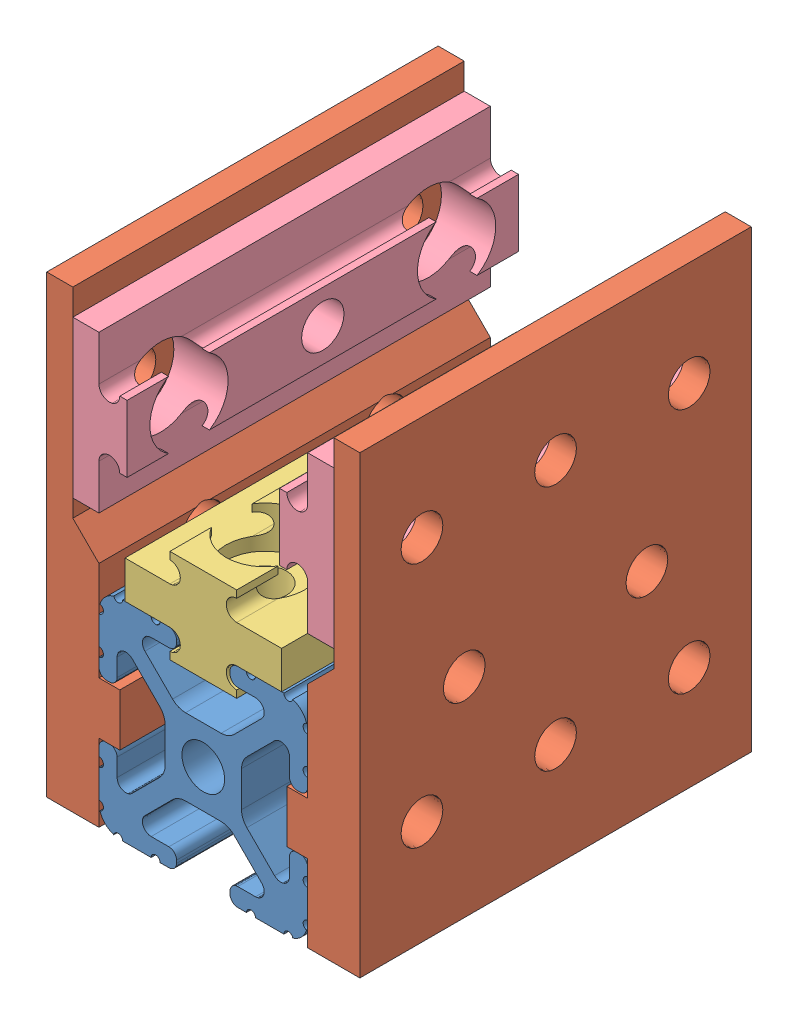
SolidWorks assembly LinearBearing_8020_pn6730, configuration Default. Lengths in mm.
Overall size (38.1 55.35 47.62).
6 component instances, 4 part files, 15 mates.
Components (placement in the parent):
- T-Slotted Framing_1.875-1: T-Slotted Framing_1.875 [47065T411] at origin size (25.4 25.4 47.62)
- BearingSide-1: BearingSide [Default] at (-19.05 -12.7 -23.8125) size (8.89 55.35 47.62)
- BearingSide-2: BearingSide [Default] at (19.05 -12.7 23.8125) x (-1 0 0) z (0 0 -1) size (8.89 55.35 47.62)
- Pad_Bearing_Upper-1: Pad_Bearing_Upper [Default] at (0 14.986 0) x (0 1 0) z (0 0 1) size (11.43 19.05 47.62)
- Pad_Bearing-1: Pad_Bearing [Default] at (15.875 29.9466 0) size (6.6 19.05 47.62)
- Pad_Bearing-2: Pad_Bearing [Default] at (-15.875 29.9466 0) x (-1 0 0) z (0 0 -1) size (6.6 19.05 47.62)
Mates (geometry in assembly coordinates):
- Coincident1: coincident: plane of T-Slotted Framing_1.875-1 through (4.1904 -11.7608 23.8125) normal (0 0 1); plane of BearingSide-1 through (-19.05 -12.7 23.8125) normal (0 0 1)
- Coincident2: coincident: plane of T-Slotted Framing_1.875-1 through (-4.1904 -12.7 23.8125) normal (0 -1 0); plane of BearingSide-1 through (-12.7 -12.7 23.8125) normal (0 -1 0)
- Coincident3: coincident anti-aligned: plane of T-Slotted Framing_1.875-1 through (-12.7 -4.1904 23.8125) normal (-1 0 0); plane of BearingSide-1 through (-12.7 -3.302 23.8125) normal (1 0 0)
- Coincident4: coincident: plane of T-Slotted Framing_1.875-1 through (4.1904 -11.7608 23.8125) normal (0 0 1); plane of BearingSide-2 through (19.05 -12.7 23.8125) normal (0 0 1)
- Coincident5: coincident: plane of T-Slotted Framing_1.875-1 through (4.1904 -12.7 23.8125) normal (0 -1 0); plane of BearingSide-2 through (12.7 -12.7 -23.8125) normal (0 -1 0)
- Coincident6: coincident anti-aligned: plane of T-Slotted Framing_1.875-1 through (12.7 -4.1904 23.8125) normal (1 0 0); plane of BearingSide-2 through (12.7 -3.302 -23.8125) normal (-1 0 0)
- Coincident7: coincident aligned: plane of T-Slotted Framing_1.875-1 through (4.1904 -11.7608 23.8125) normal (0 0 1); plane of Pad_Bearing_Upper-1 through (-4.064 11.43 23.8125) normal (0 0 1)
- Coincident8: coincident anti-aligned: plane of T-Slotted Framing_1.875-1 through (-4.1904 12.7 23.8125) normal (0 1 0); plane of Pad_Bearing_Upper-1 through (-9.525 12.7 23.8125) normal (0 -1 0)
- Coincident9: coincident anti-aligned: plane of Pad_Bearing_Upper-1 through (0 14.986 0) normal (-1 0 0)
- Concentric1: concentric: cylinder of BearingSide-2 through (10.16 29.9466 0) axis (1 0 0) radius 2.54; cylinder of Pad_Bearing-1 through (15.875 29.9466 0) axis (-1 0 0) radius 2.5797
- Coincident10: coincident: plane of BearingSide-2 through (15.875 42.6466 -23.8125) normal (-1 0 0); plane of Pad_Bearing-1 through (15.875 20.4216 23.8125) normal (1 0 0)
- Parallel1: parallel aligned: plane of BearingSide-2 through (19.05 -12.7 23.8125) normal (0 0 1); plane of Pad_Bearing-1 through (11.43 34.0106 23.8125) normal (0 0 1)
- Concentric2: concentric: cylinder of BearingSide-1 through (-10.16 29.9466 0) axis (-1 0 0) radius 2.54; cylinder of Pad_Bearing-2 through (-15.875 29.9466 0) axis (1 0 0) radius 2.5797
- Coincident11: coincident: plane of BearingSide-1 through (-15.875 42.6466 23.8125) normal (1 0 0); plane of Pad_Bearing-2 through (-15.875 6.217 -9.7297) normal (-1 0 0)
- Parallel2: parallel aligned: plane of BearingSide-1 through (-19.05 -12.7 23.8125) normal (0 0 1); plane of Pad_Bearing-2
